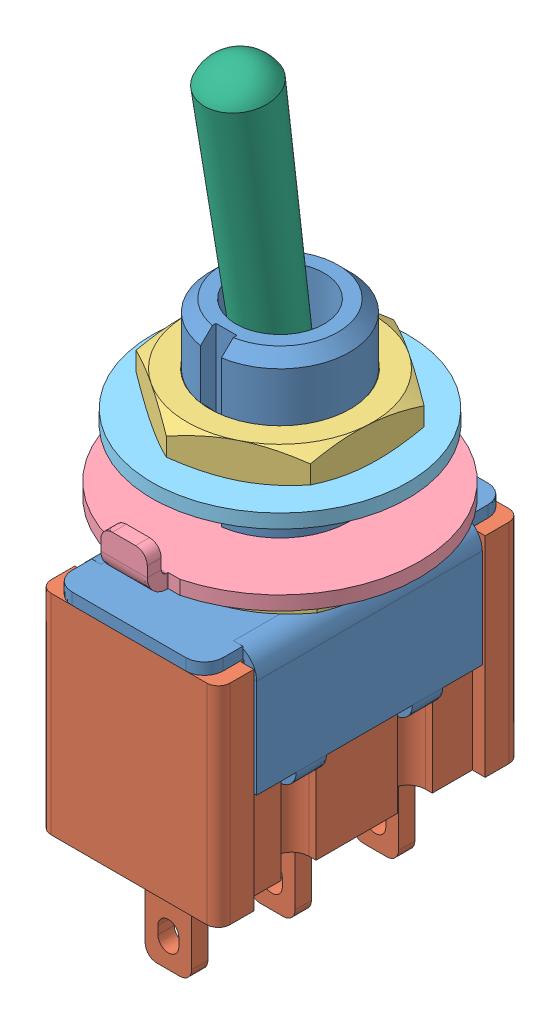
SolidWorks assembly T-Switch, configuration 00. Lengths in mm.
Overall size (12.12 32.79 13.21).
7 component instances, 6 part files, 13 mates.
Components (placement in the parent):
- Bush^T-Switch-1: Bush^T-Switch [00] at origin size (7.7 14.9 13) (virtual)
- Body^T-Switch-1: Body^T-Switch [00] at (0 -0.5 0) size (7.7 13.2 13) (virtual)
- Hex Nut M6x0.75^T-Switch-1: Hex Nut M6x0.75^T-Switch [00] at (0 0.7502 0) x (-0.514434 0 0.85753) z (-0.85753 0 -0.514434) size (8 1.5 9.24) (virtual)
- Lock Washer^T-Switch-1: Lock Washer^T-Switch [00] at (0 2.1002 0) size (12 1.8 12.71) (virtual)
- IntTooth Lock Washer M6B^T-Switch-1: IntTooth Lock Washer M6B^T-Switch [00] at (0 4.1977 0) x (0.99992 0 -0.012616) z (0.012616 0 0.99992) size (11 0.6 11) (virtual)
- Hex Nut M6x0.75^T-Switch-2: Hex Nut M6x0.75^T-Switch [00] at (0 5.5477 0) x (-0.551582 0 0.834121) z (-0.834121 0 -0.551582) size (8 1.5 9.24) (virtual)
- Actuator^T-Switch-1: Actuator^T-Switch [00] at (0 5.0056 0) x (1 0 0) z (0 -0.139173 0.990268) size (4.2 16.02 4.2) (virtual)
Mates (geometry in assembly coordinates):
- Совпадение1: coincident anti-aligned: plane of Bush^T-Switch-1 through (2.45 -0.5 5.7) normal (0 -1 0); plane of Body^T-Switch-1 through (0 -0.5 0) normal (0 1 0)
- Совпадение2: coincident aligned: plane of Bush^T-Switch-1 through (0 0 0) normal (1 0 0); plane of Body^T-Switch-1 through (0 -0.5 0) normal (1 0 0)
- Совпадение3: coincident aligned: plane of Bush^T-Switch-1 through (0 0 0) normal (0 0 1); plane of Body^T-Switch-1 through (0 -0.5 0) normal (0 0 1)
- Концентричный1: concentric anti-aligned: cylinder of Bush^T-Switch-1 through (0 8.9 0) axis (0 -1 0) radius 3; cylinder of Hex Nut M6x0.75^T-Switch-1 through (0 1.5002 0) axis (0 1 0) radius 2.625
- Совпадение4: coincident anti-aligned: plane of Hex Nut M6x0.75^T-Switch-1 through (0 1.5002 0) normal (0 1 0); plane of Lock Washer^T-Switch-1 through (0 1.5002 0) normal (0 -1 0)
- Концентричный2: concentric anti-aligned: cylinder of Bush^T-Switch-1 through (0 8.9 0) axis (0 -1 0) radius 3; cylinder of Lock Washer^T-Switch-1 through (0 1.5002 0) axis (0 1 0) radius 2.975
- Концентричный3: concentric aligned: cylinder of Bush^T-Switch-1 through (0 8.9 0) axis (0 -1 0) radius 3; cylinder of IntTooth Lock Washer M6B^T-Switch-1 through (0 4.7977 0) axis (0 -1 0) radius 3.1
- Концентричный4: concentric anti-aligned: cylinder of Bush^T-Switch-1 through (0 8.9 0) axis (0 -1 0) radius 3; cylinder of Hex Nut M6x0.75^T-Switch-2 through (0 6.2977 0) axis (0 1 0) radius 2.625
- Совпадение5: coincident anti-aligned: plane of IntTooth Lock Washer M6B^T-Switch-1 through (0 4.7977 0) normal (0 1 0); plane of Hex Nut M6x0.75^T-Switch-2 through (0 4.7977 0) normal (0 -1 0)
- Совпадение6: coincident: plane of Bush^T-Switch-1 through (0 0 0) normal (0 0 1); point of Actuator^T-Switch-1
- Касательность1: tangent: circle of Bush^T-Switch-1; sphere of Actuator^T-Switch-1
- Совпадение7: coincident aligned: plane of Bush^T-Switch-1 through (0 0 0) normal (1 0 0); plane of Actuator^T-Switch-1
- Граничный угол1: limit planar angle = 0.139626 rad aligned: plane of Actuator^T-Switch-1 through (0 5.0056 0) normal (0 -0.139173 0.990268); plane of Bush^T-Switch-1 through (0 0 0) normal (0 0 1)
